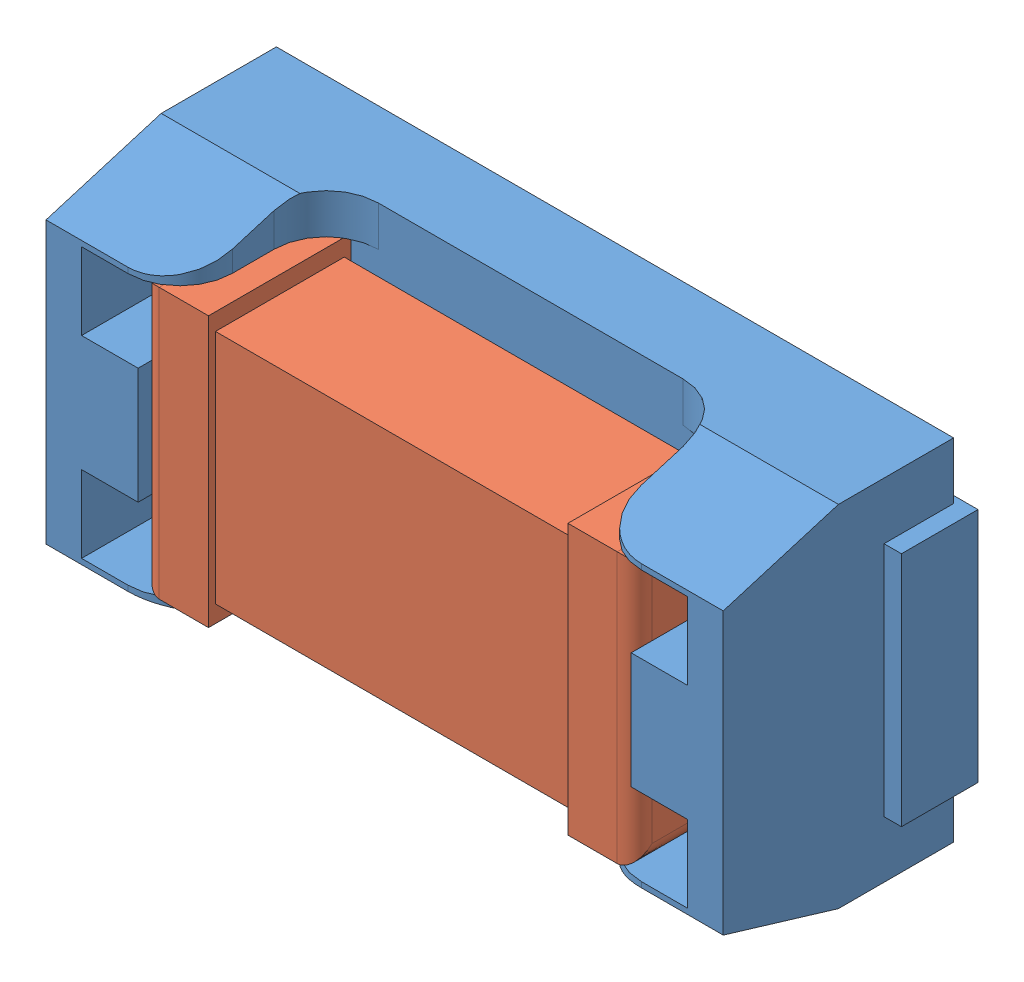
SolidWorks assembly fuseasm, configuration Défaut. Lengths in mm.
Overall size (10.43 5.03 3.41).
2 component instances, 2 part files, 3 mates.
Components (placement in the parent):
- FusePart-1: FusePart [Défaut] at (-0.1029 -0.6174 8.82) size (10.43 5.03 3.41)
- fuse-real-1: fuse-real [Défaut] at (-0.1013 -0.6161 10.03) size (7.08 3.88 2.05)
Mates (geometry in assembly coordinates):
- Coïncidente1: coincident: plane of FusePart-1 through (3.4387 -0.6174 10.03) normal (-1 0 0); plane of fuse-real-1 through (3.4387 -2.5561 12.08) normal (1 0 0)
- Coïncidente2: coincident: plane of FusePart-1 through (-0.1029 -2.5561 10.03) normal (0 1 0); plane of fuse-real-1 through (-3.6413 -2.5561 12.08) normal (0 -1 0)
- Coïncidente3: coincident anti-aligned: plane of FusePart-1 through (-0.1029 -0.6174 10.03) normal (0 0 1); plane of fuse-real-1 through (-0.1013 -0.6161 10.03) normal (0 0 -1)
